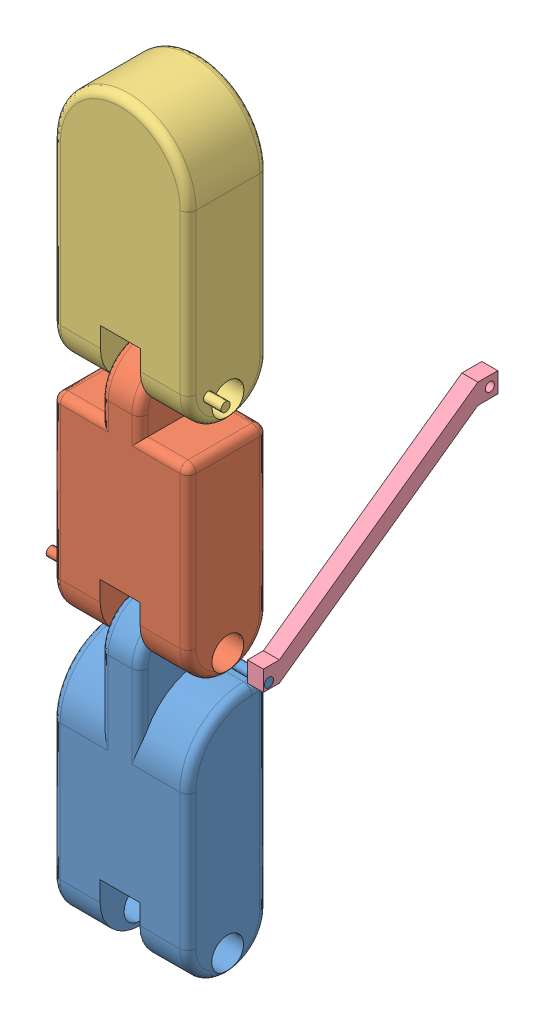
SolidWorks assembly Assem3, configuration Default. Lengths in mm.
Overall size (214.2 937 366.97).
4 component instances, 4 part files, 6 mates.
Components (placement in the parent):
- bottomIndex2-1: bottomIndex2 [Default] at (88.6261 142.2554 369.3769) size (192.89 374 100.1)
- upIndex2-1: upIndex2 [Default] at (88.8261 443.2554 369.3769) size (193.09 324 100.1)
- topIndex2-1: topIndex2 [Default] at (89.0261 719.2554 369.3769) size (193.09 335 100.1)
- link2-1: link2 [Default] at (175.4261 489.7335 12.4097) x (0 -1 0) z (0 0 1) size (202.48 20 293.97)
Mates (geometry in assembly coordinates):
- Concentric1: concentric: cylinder of assembly; cylinder of assembly; cylinder of bottomIndex2-1 through (3.6261 343.2554 319.3769) axis (1 0 0) radius 20; cylinder of upIndex2-1 through (173.8261 343.2554 319.3769) axis (-1 0 0) radius 20
- Coincident1: coincident: plane of assembly; plane of assembly; plane of bottomIndex2-1 through (63.8261 292.2554 269.3769) normal (-1 0 0); plane of upIndex2-1 through (63.8261 293.2554 269.3769) normal (1 0 0)
- Concentric2: concentric: cylinder of assembly; cylinder of assembly; cylinder of upIndex2-1 through (2.7397 619.2554 319.3769) axis (1 0 0) radius 20; cylinder of topIndex2-1 through (174.0261 619.2554 319.3769) axis (-1 0 0) radius 20
- Coincident2: coincident: plane of assembly; plane of assembly; plane of upIndex2-1 through (64.0261 568.2554 269.3769) normal (-1 0 0); plane of topIndex2-1 through (64.0261 569.2554 269.3769) normal (1 0 0)
- Concentric3: concentric: cylinder of assembly; cylinder of assembly; cylinder of bottomIndex2-1 through (195.4261 307.2554 289.3769) axis (-1 0 0) radius 5.75; cylinder of link2-1 through (175.4261 307.2554 289.3769) axis (1 0 0) radius 5.75
- Coincident3: coincident: plane of assembly; plane of assembly; plane of bottomIndex2-1 through (195.4261 307.2554 289.3769) normal (1 0 0); plane of link2-1 through (195.4261 489.7335 12.4097) normal (1 0 0)
